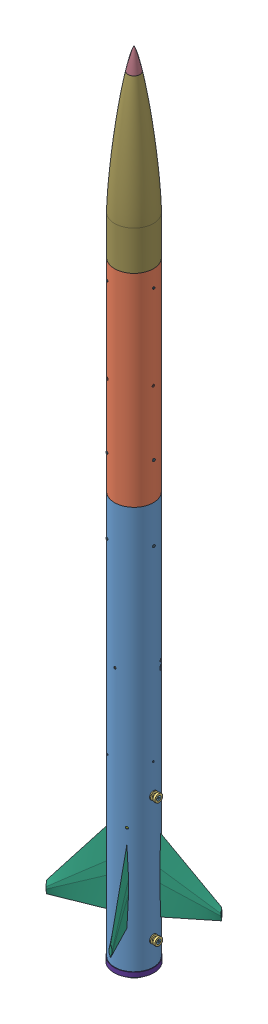
SolidWorks assembly Skipper_1B, configuration Default. Lengths in mm.
Overall size (229.44 1630.61 229.44).
187 component instances, 72 part files, 15 mates.
Components (placement in the parent):
- S1B_Airframe-1: S1B_Airframe [Default] at origin size (229.44 1236.87 229.44)
  - S1B_Aft_Body_Tube-2: S1B_Aft_Body_Tube [Default] at origin size (79.25 822.53 79.25)
  - S1B_Forward_Body_Tube-1: S1B_Forward_Body_Tube [Default] at (0 822.5282 0) size (79.25 414.34 79.25)
  - S1B_Railguide-1: S1B_Railguide [Default] at (39.8526 50.8 0) size (19.05 19 19)
    - S1B_Railguide_Bolt-1: S1B_Railguide_Bolt [Default] at origin size (10.92 16 16)
    - S1B_Welded_Nut_Railguide-1: S1B_Welded_Nut_Railguide [Default] at (-2.6264 0 0) x (0 0 1) z (-1 0 0) size (19 19 11)
    - S1B_10-32_Flathead_RailguideScrew-2: S1B_10-32_Flathead_RailguideScrew [91099A365] at (1.397 0 0) x (-1 0 0) z (0 0 -1) size (19.05 8.95 8.95)
  - S1B_Railguide-2: S1B_Railguide [Default] at (39.8526 304.8 0) size (19.05 19 19)
    - S1B_Railguide_Bolt-1: S1B_Railguide_Bolt [Default] at origin size (10.92 16 16)
    - S1B_Welded_Nut_Railguide-1: S1B_Welded_Nut_Railguide [Default] at (-2.6264 0 0) x (0 0 1) z (-1 0 0) size (19 19 11)
    - S1B_10-32_Flathead_RailguideScrew-2: S1B_10-32_Flathead_RailguideScrew [91099A365] at (1.397 0 0) x (-1 0 0) z (0 0 -1) size (19.05 8.95 8.95)
  - S1B_Fin_Representation_2-2: S1B_Fin_Representation_2 [Default] at (19.812 150.622 34.3154) x (0.5 0 0.866025) z (-0.866025 0 0.5) size (91.39 148.58 5.04)
  - S1B_Fin_Representation_2-3: S1B_Fin_Representation_2 [Default] at (-34.3154 150.622 19.812) x (-0.866025 0 0.5) z (-0.5 0 -0.866025) size (91.39 148.58 5.04)
  - S1B_Fin_Representation_2-4: S1B_Fin_Representation_2 [Default] at (-19.812 150.622 -34.3154) x (-0.5 0 -0.866025) z (0.866025 0 -0.5) size (91.39 148.58 5.04)
  - S1B_Fin_Representation_2-5: S1B_Fin_Representation_2 [Default] at (34.3154 150.622 -19.812) x (0.866025 0 -0.5) z (0.5 0 0.866025) size (91.39 148.58 5.04)
- S1B_Nose_Cone-1: S1B_Nose_Cone [Default] at (0 1169.2636 0) size (80.74 442.25 79.45)
  - S1B_Nose_Cone_Shoulder_Tube-1: S1B_Nose_Cone_Shoulder_Tube [Default] at origin size (76.28 147.82 76.28)
  - S1B_Nose_Cone_Bulkhead-1: S1B_Nose_Cone_Bulkhead [Default] at (0 141.4653 0) size (73.03 6.35 73.03)
  - S1B_Nose_Cone_Recovery_Eyebolt_3014T45_Steel Eyebolt with Shoulder - for Lifting-1: S1B_Nose_Cone_Recovery_Eyebolt_3014T45_Steel Eyebolt with Shoulder - for Lifting [3014T45] at (0 117.6528 0) x (-1 0 0) z (0 0 1) size (30.16 64.29 14.29)
  - S1B_Nose_Cone_Recovery_Nut_95462A029_Medium-Strength Steel Hex Nut-1: S1B_Nose_Cone_Recovery_Nut_95462A029_Medium-Strength Steel Hex Nut [95462A029] at (0 151.6856 0) x (1 0 0) z (0 1 0) size (11.11 12.83 5.56)
  - S1B_Nose_Cone_Recovery_Washer_90107A029_316 Stainless Steel Washer-1: S1B_Nose_Cone_Recovery_Washer_90107A029_316 Stainless Steel Washer [90107A029] at (0 147.8153 0) x (-1 0 0) z (0 0 -1) size (15.88 1.09 15.88)
  - S1B_Nose_Cone-1: S1B_Nose_Cone [Default] at (0 442.2522 0) x (0 -1 0) z (0 0 -1) size (330.2 79.45 79.45)
  - S1B_Nose_Cone_Tip-1: S1B_Nose_Cone_Tip [Default] at (0 442.2521 0) x (0 -1 0) z (0 0 1) size (44.45 24.48 24.48)
  - S1B_Shear_Pin-1: S1B_Shear_Pin [Default] at (39.7256 33.8074 0) x (0 -1 0) z (-1 0 0) size (3.81 3.83 10.38)
  - S1B_Shear_Pin-2: S1B_Shear_Pin [Default] at (-19.8628 33.8074 -34.4034) x (0 -1 0) z (0.5 0 0.866025) size (3.81 3.83 10.38)
  - S1B_Shear_Pin-3: S1B_Shear_Pin [Default] at (-19.8628 33.8074 34.4034) x (0 -1 0) z (0.5 0 -0.866025) size (3.81 3.83 10.38)
- S1B_Electronics_Bay-1: S1B_Electronics_Bay [Default] at (0 387.6803 0) size (104.18 564.06 103.27)
  - S1B_Electronics_Bay_Aft_Bulkhead-1: S1B_Electronics_Bay_Aft_Bulkhead [Default] at origin size (76.45 6.35 76.45)
  - S1B_Electronics_Bay_Spacer_Aft_Bulkhead-1: S1B_Electronics_Bay_Spacer_Aft_Bulkhead [Default] at (0 353.8981 0) size (76.71 9.53 76.71)
  - S1B_Electronics_Bay_Spacer_Forward_Bulkhead-1: S1B_Electronics_Bay_Spacer_Forward_Bulkhead [Default] at (0 506.2727 0) size (76.71 9.53 76.71)
  - S1B_Fat_Bulkhead_Coupler-2: S1B_Fat_Bulkhead_Coupler [Default] at (0 363.4231 0) size (76.45 142.85 76.45)
  - S1B_Electronics_Bay_3014T45_Steel Eyebolt with Shoulder - for Lifting-1: S1B_Electronics_Bay_3014T45_Steel Eyebolt with Shoulder - for Lifting [3014T45] at (0 539.6102 18.415) size (30.16 64.29 14.29)
  - S1B_Electronics_Bay_90107A029_316 Stainless Steel Washer-1: S1B_Electronics_Bay_90107A029_316 Stainless Steel Washer [90107A029] at (0 505.1805 18.415) x (-1 0 0) z (0 0 -1) size (15.88 1.09 15.88)
  - S1B_Electronics_Bay_95462A029_Medium-Strength Steel Hex Nut-1: S1B_Electronics_Bay_95462A029_Medium-Strength Steel Hex Nut [95462A029] at (0 502.4024 18.415) x (1 0 0) z (0 1 0) size (11.11 12.83 5.56)
  - S1B_Electronics_Bay_98804A006_18-8 Stainless Steel Threaded Rod-1: S1B_Electronics_Bay_98804A006_18-8 Stainless Steel Threaded Rod [98804A006] at (0 257.975 -29.464) x (1 0 0) z (0 -1 0) size (3.17 3.17 534.7)
  - S1B_Electronics_Bay_91841A006_18-8 Stainless Steel Hex Nut-1: S1B_Electronics_Bay_91841A006_18-8 Stainless Steel Hex Nut [91841A006] at (0 517.8218 -29.464) x (-1 0 0) z (0 0 -1) size (7.94 2.78 9.17)
  - S1B_Electronics_Bay_90107A006_316 Stainless Steel Washer-1: S1B_Electronics_Bay_90107A006_316 Stainless Steel Washer [90107A006] at (0 515.7977 -29.464) size (7.14 0.64 7.14)
  - S1B_Electronics_Bay_90107A006_316 Stainless Steel Washer-4: S1B_Electronics_Bay_90107A006_316 Stainless Steel Washer [90107A006] at (25.5166 515.7977 14.732) x (-0.5 0 0.866025) z (-0.866025 0 -0.5) size (7.14 0.64 7.14)
  - S1B_Electronics_Bay_90107A006_316 Stainless Steel Washer-5: S1B_Electronics_Bay_90107A006_316 Stainless Steel Washer [90107A006] at (-25.5166 515.7977 14.732) x (-0.5 0 -0.866025) z (0.866025 0 -0.5) size (7.14 0.64 7.14)
  - S1B_Electronics_Bay_91841A006_18-8 Stainless Steel Hex Nut-2: S1B_Electronics_Bay_91841A006_18-8 Stainless Steel Hex Nut [91841A006] at (25.5166 517.8218 14.732) x (0.5 0 -0.866025) z (0.866025 0 0.5) size (7.94 2.78 9.17)
  - S1B_Electronics_Bay_91841A006_18-8 Stainless Steel Hex Nut-3: S1B_Electronics_Bay_91841A006_18-8 Stainless Steel Hex Nut [91841A006] at (-25.5166 517.8218 14.732) x (0.5 0 0.866025) z (-0.866025 0 0.5) size (7.94 2.78 9.17)
  - S1B_Electronics_Bay_98804A006_18-8 Stainless Steel Threaded Rod-4: S1B_Electronics_Bay_98804A006_18-8 Stainless Steel Threaded Rod [98804A006] at (25.5166 257.975 14.732) x (-0.5 0 0.866025) z (0 -1 0) size (3.17 3.17 534.7)
  - S1B_Electronics_Bay_98804A006_18-8 Stainless Steel Threaded Rod-5: S1B_Electronics_Bay_98804A006_18-8 Stainless Steel Threaded Rod [98804A006] at (-25.5166 257.975 14.732) x (-0.5 0 -0.866025) z (0 -1 0) size (3.17 3.17 534.7)
  - S1B_Electronics_Bay_90107A006_316 Stainless Steel Washer-12: S1B_Electronics_Bay_90107A006_316 Stainless Steel Washer [90107A006] at (0 0 -29.464) x (1 0 0) z (0 0 -1) size (7.14 0.64 7.14)
  - S1B_Electronics_Bay_91841A006_18-8 Stainless Steel Hex Nut-14: S1B_Electronics_Bay_91841A006_18-8 Stainless Steel Hex Nut [91841A006] at (0 -2.0241 -29.464) x (-1 0 0) z (0 0 1) size (7.94 2.78 9.17)
  - S1B_Electronics_Bay_90107A006_316 Stainless Steel Washer-13: S1B_Electronics_Bay_90107A006_316 Stainless Steel Washer [90107A006] at (25.5166 0 14.732) x (-0.5 0 0.866025) z (0.866025 0 0.5) size (7.14 0.64 7.14)
  - S1B_Electronics_Bay_90107A006_316 Stainless Steel Washer-14: S1B_Electronics_Bay_90107A006_316 Stainless Steel Washer [90107A006] at (-25.5166 0 14.732) x (-0.5 0 -0.866025) z (-0.866025 0 0.5) size (7.14 0.64 7.14)
  - S1B_Electronics_Bay_91841A006_18-8 Stainless Steel Hex Nut-15: S1B_Electronics_Bay_91841A006_18-8 Stainless Steel Hex Nut [91841A006] at (25.5166 -2.0241 14.732) x (0.5 0 -0.866025) z (-0.866025 0 -0.5) size (7.94 2.78 9.17)
  - S1B_Electronics_Bay_91841A006_18-8 Stainless Steel Hex Nut-16: S1B_Electronics_Bay_91841A006_18-8 Stainless Steel Hex Nut [91841A006] at (-25.5166 -2.0241 14.732) x (0.5 0 0.866025) z (0.866025 0 -0.5) size (7.94 2.78 9.17)
  - S1B_Electronics_Bay_Avionics_Stack-1: S1B_Electronics_Bay_Avionics_Stack [Default] at (8.2928 -12.2914 -69.8691) size (104.18 344.14 103.27)
    - S1B_Flight_Power_Stack_Assy-1: S1B_Flight_Power_Stack_Assy [Default] at (-4.2933 16.5157 -11.6983) size (58.99 80 57.67)
      - S1B_Power_Stack-1: S1B_Power_Stack [Default] at (-4.1095 89.1616 81.6309) size (58.99 80 52.18)
      - S1B_9V Battery-1: S1B_9V Battery [Default] at (-5.5953 51.787 105.8736) x (0 0 -1) z (0 -1 0) size (47.57 16.87 26.11)
      - S1B_LiPo_A1-1: S1B_LiPo_A1 [Default] at (-22.7297 11.3191 64.2994) x (0 1 0) z (0 0 -1) size (72.97 12.27 33.73)
      - S1B_9V Battery-2: S1B_9V Battery [Default] at (-5.5953 23.6758 105.8736) x (0 0 -1) z (0 -1 0) size (47.57 16.87 26.11)
    - S1B_Fight_Computer_Stack_Assy-1: S1B_Fight_Computer_Stack_Assy [Default] at (37.1119 269.2904 8.8488) x (0.5 0 0.866025) z (0 -1 0) size (74.68 77.18 120)
      - S1B_6.86mm_Nut_3mm_Hole-7: S1B_6.86mm_Nut_3mm_Hole [Default] at (49.4605 62.5264 50.3494) x (0.433013 -0.75 0.5) z (-0.25 0.433013 0.866025) size (7.92 1.91 6.86)
      - S1B_6.86mm_Nut_3mm_Hole-10: S1B_6.86mm_Nut_3mm_Hole [Default] at (38.5881 85.168 145.066) x (-0.433013 0.75 -0.5) z (-0.25 0.433013 0.866025) size (7.92 1.91 6.86)
      - S1B_6.86mm_Nut_3mm_Hole-11: S1B_6.86mm_Nut_3mm_Hole [Default] at (36.9383 84.2155 50.3494) x (0.433013 -0.75 -0.5) z (0.25 -0.433013 0.866025) size (7.92 1.91 6.86)
      - S1B_6.86mm_Nut_3mm_Hole-12: S1B_6.86mm_Nut_3mm_Hole [Default] at (49.4605 62.5264 145.066) x (0.433013 -0.75 -0.5) z (0.25 -0.433013 0.866025) size (7.92 1.91 6.86)
      - S1B_Ruber_Washer_3mm-5: S1B_Ruber_Washer_3mm [Default] at (53.7083 64.9789 145.066) x (-0.5 0.866025 0) z (0 0 1) size (6 1.25 6)
      - S1B_Ruber_Washer_3mm-6: S1B_Ruber_Washer_3mm [Default] at (41.1861 86.668 145.066) x (-0.5 0.866025 0) z (0 0 1) size (6 1.25 6)
      - S1B_Ruber_Washer_3mm-7: S1B_Ruber_Washer_3mm [Default] at (53.7083 64.9789 50.3494) x (-0.5 0.866025 0) z (0 0 1) size (6 1.25 6)
      - S1B_Ruber_Washer_3mm-8: S1B_Ruber_Washer_3mm [Default] at (41.1861 86.668 50.3494) x (-0.5 0.866025 0) z (0 0 1) size (6 1.25 6)
      - S1B_Avionics_Stack - AIM-1: S1B_Avionics_Stack - AIM [Default] at (55.5493 84.6273 26.5774) x (-0.5 -0.866025 0) z (0 0 1) size (33.58 52.18 120)
      - S1B_AimXtra-1: S1B_AimXtra [Default] at (39.9161 88.8677 47.8094) x (0 0 1) z (-0.5 0.866025 0) size (102.34 16.13 30.12)
      - S1B_6.86mm_Nut_3mm_Hole-13: S1B_6.86mm_Nut_3mm_Hole [Default] at (13.2223 66.1787 125.5587) x (0.433013 0.75 -0.5) z (0.25 0.433013 0.866025) size (7.92 1.91 6.86)
      - S1B_6.86mm_Nut_3mm_Hole-14: S1B_6.86mm_Nut_3mm_Hole [Default] at (24.7223 86.0973 125.5587) x (0.433013 0.75 -0.5) z (0.25 0.433013 0.866025) size (7.92 1.91 6.86)
      - S1B_6.86mm_Nut_3mm_Hole-15: S1B_6.86mm_Nut_3mm_Hole [Default] at (13.2223 66.1787 69.0624) x (0.433013 0.75 0.5) z (-0.25 -0.433013 0.866025) size (7.92 1.91 6.86)
      - S1B_6.86mm_Nut_3mm_Hole-16: S1B_6.86mm_Nut_3mm_Hole [Default] at (24.7223 86.0973 67.5587) x (0.433013 0.75 -0.5) z (0.25 0.433013 0.866025) size (7.92 1.91 6.86)
      - S1B_Ruber_Washer_3mm-9: S1B_Ruber_Washer_3mm [Default] at (21.3404 88.0498 67.5587) x (0.5 0.866025 0) z (0 0 1) size (6 1.25 6)
      - S1B_Ruber_Washer_3mm-10: S1B_Ruber_Washer_3mm [Default] at (9.8404 68.1312 69.0624) x (0.5 0.866025 0) z (0 0 1) size (6 1.25 6)
      - S1B_Ruber_Washer_3mm-11: S1B_Ruber_Washer_3mm [Default] at (21.3404 88.0498 125.5587) x (0.5 0.866025 0) z (0 0 1) size (6 1.25 6)
      - S1B_Ruber_Washer_3mm-12: S1B_Ruber_Washer_3mm [Default] at (9.8404 68.1312 125.5587) x (0.5 0.866025 0) z (0 0 1) size (6 1.25 6)
      - S1B_Avionics_Stack-1: S1B_Avionics_Stack [Default] at (4.7361 84.6273 26.5774) size (33.58 52.18 120)
      - S1B_RBP2W-1: S1B_RBP2W [Default] at (13.9471 81.3442 101.7819) x (0 0 -1) z (0.5 0.866025 0) size (65 5.1 31.05)
      - S1B_6.86mm_Nut_3mm_Hole-17: S1B_6.86mm_Nut_3mm_Hole [Default] at (44.7248 57.1953 44.9616) x (-0.868623 0 -0.495473) z (-0.495473 0 0.868623) size (7.92 1.91 6.86)
      - S1B_6.86mm_Nut_3mm_Hole-18: S1B_6.86mm_Nut_3mm_Hole [Default] at (44.7248 57.1953 59.1316) x (-0.868623 0 -0.495473) z (-0.495473 0 0.868623) size (7.92 1.91 6.86)
      - S1B_6.86mm_Nut_3mm_Hole-19: S1B_6.86mm_Nut_3mm_Hole [Default] at (12.4948 57.1953 59.1316) x (-0.868623 0 -0.495473) z (-0.495473 0 0.868623) size (7.92 1.91 6.86)
      - S1B_6.86mm_Nut_3mm_Hole-20: S1B_6.86mm_Nut_3mm_Hole [Default] at (12.4948 57.1953 44.9616) x (-0.855922 0 -0.517105) z (-0.517105 0 0.855922) size (7.92 1.91 6.86)
      - S1B_Ruber_Washer_3mm-13: S1B_Ruber_Washer_3mm [Default] at (12.4948 52.0403 44.9616) size (6 1.25 6)
      - S1B_Ruber_Washer_3mm-14: S1B_Ruber_Washer_3mm [Default] at (44.7248 52.0403 44.9616) size (6 1.25 6)
      - S1B_Ruber_Washer_3mm-15: S1B_Ruber_Washer_3mm [Default] at (44.7248 52.0403 59.1316) size (6 1.25 6)
      - S1B_Ruber_Washer_3mm-16: S1B_Ruber_Washer_3mm [Default] at (12.4948 52.0403 59.1316) size (6 1.25 6)
      - S1B_Avionics_Stack - EasyMini-1: S1B_Avionics_Stack - EasyMini [Default] at (30.1427 40.6218 26.5774) x (-0.5 0.866025 0) z (0 0 1) size (33.58 52.18 120)
      - S1B_EZMINI-1: S1B_EZMINI [Default] at (28.7345 50.2403 46.2994) x (1 0 0) z (0 0 -1) size (38.23 12.5 21.18)
    - S1B_Sensor_Power_Stack_Assy-1: S1B_Sensor_Power_Stack_Assy [Default] at (-32.7742 223.4603 27.9192) size (57.8 36.27 57.54)
      - S1B_Sensor_Power_Stack-1: S1B_Sensor_Power_Stack [Default] at (24.3714 13.7485 42.0133) size (57.8 28.96 55.69)
      - S1B_9V Battery-1: S1B_9V Battery [Default] at (37.7064 32.0365 66.7275) x (0 0 -1) z (1 0 0) size (47.57 16.87 26.11)
      - S1B_9V Battery-2: S1B_9V Battery [Default] at (37.7064 12.6309 66.7275) x (0 0 -1) z (1 0 0) size (47.57 16.87 26.11)
    - S1B_Sensor_Stack_Assy-1: S1B_Sensor_Stack_Assy [Default] at (-68.238 266.8297 115.4931) x (-0.5 0 -0.866025) z (0.866025 0 -0.5) size (58.99 80 52.18)
      - S1B_Sensor_Stack_T_Mount_A2-1: S1B_Sensor_Stack_T_Mount_A2 [Default] at (9.5389 -1.0891 74.5991) size (58.99 80 52.18)
      - S1B_6.86mm_Nut_3mm_Hole-1: S1B_6.86mm_Nut_3mm_Hole [Default] at (6.8862 79.7859 74.7996) x (0.75 0.5 0.433013) z (0.433013 -0.866025 0.25) size (7.92 1.91 6.86)
      - S1B_Ruber_Washer_3mm-1: S1B_Ruber_Washer_3mm [Default] at (28.3048 79.7859 83.7015) x (0.75 -0.5 0.433013) z (0.433013 0.866025 0.25) size (6 1.25 6)
      - S1B_Ruber_Washer_3mm-2: S1B_Ruber_Washer_3mm [Default] at (8.3862 79.7859 72.2015) x (0.75 -0.5 0.433013) z (0.433013 0.866025 0.25) size (6 1.25 6)
      - S1B_Ruber_Washer_3mm-3: S1B_Ruber_Washer_3mm [Default] at (28.3048 18.0359 83.7015) x (0.75 -0.5 0.433013) z (0.433013 0.866025 0.25) size (6 1.25 6)
      - S1B_Ruber_Washer_3mm-4: S1B_Ruber_Washer_3mm [Default] at (8.3862 18.0359 72.2015) x (0.75 -0.5 0.433013) z (0.433013 0.866025 0.25) size (6 1.25 6)
      - S1B_6.86mm_Nut_3mm_Hole-3: S1B_6.86mm_Nut_3mm_Hole [Default] at (26.8048 18.0359 86.2996) x (0.75 0.5 0.433013) z (0.433013 -0.866025 0.25) size (7.92 1.91 6.86)
      - S1B_6.86mm_Nut_3mm_Hole-4: S1B_6.86mm_Nut_3mm_Hole [Default] at (6.8862 18.0359 74.7996) x (0.75 0.5 0.433013) z (0.433013 -0.866025 0.25) size (7.92 1.91 6.86)
      - S1B_6.86mm_Nut_3mm_Hole-2: S1B_6.86mm_Nut_3mm_Hole [Default] at (26.8048 79.7859 86.2996) x (0.75 0.5 0.433013) z (0.433013 -0.866025 0.25) size (7.92 1.91 6.86)
      - S1B_Sensor_PCB-1: S1B_Sensor_PCB [Default] at (32.9609 14.7859 82.637) x (0 1 0) z (0.866025 0 0.5) size (68.25 2 30)
    - S1B_Blue_Damper-1: S1B_Blue_Damper [Default] at (-33.8094 18.6414 84.6011) x (0 0 -1) z (1 0 0) size (9.3 7.04 9.3)
    - S1B_Blue_Damper-19: S1B_Blue_Damper [Default] at (-33.8094 105.6772 84.6011) size (9.3 7.04 9.3)
    - S1B_Blue_Damper-22: S1B_Blue_Damper [Default] at (-33.8094 232.713 84.6011) size (9.3 7.04 9.3)
    - S1B_Blue_Damper-25: S1B_Blue_Damper [Default] at (-33.8094 268.7048 84.6011) x (-1 0 0) z (0 0 -1) size (9.3 7.04 9.3)
    - S1B_Blue_Damper-28: S1B_Blue_Damper [Default] at (-33.8094 355.7406 84.6011) size (9.3 7.04 9.3)
    - S1B_Blue_Damper-29: S1B_Blue_Damper [Default] at (17.1065 355.7406 84.4952) x (-0.5 0 -0.866025) z (0.866025 0 -0.5) size (9.3 7.04 9.3)
    - S1B_Blue_Damper-30: S1B_Blue_Damper [Default] at (-8.4431 355.7406 40.4537) x (-0.5 0 0.866025) z (-0.866025 0 -0.5) size (9.3 7.04 9.3)
    - S1B_Blue_Damper-26: S1B_Blue_Damper [Default] at (17.1065 268.7048 84.4952) x (0.5 0 0.866025) z (-0.866025 0 0.5) size (9.3 7.04 9.3)
    - S1B_Blue_Damper-27: S1B_Blue_Damper [Default] at (-8.4431 268.7048 40.4537) x (0.5 0 -0.866025) z (0.866025 0 0.5) size (9.3 7.04 9.3)
    - S1B_Blue_Damper-23: S1B_Blue_Damper [Default] at (17.1065 232.713 84.4952) x (-0.5 0 -0.866025) z (0.866025 0 -0.5) size (9.3 7.04 9.3)
    - S1B_Blue_Damper-24: S1B_Blue_Damper [Default] at (-8.4431 232.713 40.4537) x (-0.5 0 0.866025) z (-0.866025 0 -0.5) size (9.3 7.04 9.3)
    - S1B_Blue_Damper-20: S1B_Blue_Damper [Default] at (17.1065 105.6772 84.4952) x (-0.5 0 -0.866025) z (0.866025 0 -0.5) size (9.3 7.04 9.3)
    - S1B_Blue_Damper-21: S1B_Blue_Damper [Default] at (-8.4431 105.6772 40.4537) x (-0.5 0 0.866025) z (-0.866025 0 -0.5) size (9.3 7.04 9.3)
    - S1B_Blue_Damper-17: S1B_Blue_Damper [Default] at (17.1065 18.6414 84.4952) x (-0.866025 0 0.5) z (-0.5 0 -0.866025) size (9.3 7.04 9.3)
    - S1B_Blue_Damper-18: S1B_Blue_Damper [Default] at (-8.4431 18.6414 40.4537) x (0.866025 0 0.5) z (-0.5 0 0.866025) size (9.3 7.04 9.3)
  - S1B_Airframe_Threaded_Inserts_92394A113_18-8 Stainless Steel Screw-to-Expand Insert for Plastic-1: S1B_Airframe_Threaded_Inserts_92394A113_18-8 Stainless Steel Screw-to-Expand Insert for Plastic [92394A113] at (-17.5895 358.6606 -30.4659) x (0 -1 0) z (0.866025 0 -0.5) size (5.05 6.35 5.05)
  - S1B_Airframe_Bolts_90357A120_Ultra-Low-Profile Socket Head Screw-1: S1B_Airframe_Bolts_90357A120_Ultra-Low-Profile Socket Head Screw [90357A120] at (-18.3483 358.6606 -31.7802) x (0.866025 0 -0.5) z (0.5 0 0.866025) size (5.08 5.08 9.2)
  - S1B_Airframe_Threaded_Inserts_92394A113_18-8 Stainless Steel Screw-to-Expand Insert for Plastic-2: S1B_Airframe_Threaded_Inserts_92394A113_18-8 Stainless Steel Screw-to-Expand Insert for Plastic [92394A113] at (35.179 358.6606 0) x (0 -1 0) z (0 0 1) size (5.05 6.35 5.05)
  - S1B_Airframe_Threaded_Inserts_92394A113_18-8 Stainless Steel Screw-to-Expand Insert for Plastic-6: S1B_Airframe_Threaded_Inserts_92394A113_18-8 Stainless Steel Screw-to-Expand Insert for Plastic [92394A113] at (-17.5895 358.6606 30.4659) x (0 -1 0) z (-0.866025 0 -0.5) size (5.05 6.35 5.05)
  - S1B_Airframe_Bolts_90357A120_Ultra-Low-Profile Socket Head Screw-2: S1B_Airframe_Bolts_90357A120_Ultra-Low-Profile Socket Head Screw [90357A120] at (36.6966 358.6606 0) x (0 0 1) z (-1 0 0) size (5.08 5.08 9.2)
  - S1B_Airframe_Bolts_90357A120_Ultra-Low-Profile Socket Head Screw-6: S1B_Airframe_Bolts_90357A120_Ultra-Low-Profile Socket Head Screw [90357A120] at (-18.3483 358.6606 31.7802) x (-0.866025 0 -0.5) z (0.5 0 -0.866025) size (5.08 5.08 9.2)
  - S1B_Airframe_Bolts_90357A120_Ultra-Low-Profile Socket Head Screw-8: S1B_Airframe_Bolts_90357A120_Ultra-Low-Profile Socket Head Screw [90357A120] at (-18.3483 511.0606 -31.7802) x (0.866025 0 -0.5) z (0.5 0 0.866025) size (5.08 5.08 9.2)
  - S1B_Airframe_Threaded_Inserts_92394A113_18-8 Stainless Steel Screw-to-Expand Insert for Plastic-8: S1B_Airframe_Threaded_Inserts_92394A113_18-8 Stainless Steel Screw-to-Expand Insert for Plastic [92394A113] at (-17.5895 511.0606 -30.4659) x (0 -1 0) z (0.866025 0 -0.5) size (5.05 6.35 5.05)
  - S1B_Airframe_Threaded_Inserts_92394A113_18-8 Stainless Steel Screw-to-Expand Insert for Plastic-5: S1B_Airframe_Threaded_Inserts_92394A113_18-8 Stainless Steel Screw-to-Expand Insert for Plastic [92394A113] at (35.179 511.0606 0) x (0 -1 0) z (0 0 1) size (5.05 6.35 5.05)
  - S1B_Airframe_Threaded_Inserts_92394A113_18-8 Stainless Steel Screw-to-Expand Insert for Plastic-7: S1B_Airframe_Threaded_Inserts_92394A113_18-8 Stainless Steel Screw-to-Expand Insert for Plastic [92394A113] at (-17.5895 511.0606 30.4659) x (0 -1 0) z (-0.866025 0 -0.5) size (5.05 6.35 5.05)
  - S1B_Airframe_Bolts_90357A120_Ultra-Low-Profile Socket Head Screw-5: S1B_Airframe_Bolts_90357A120_Ultra-Low-Profile Socket Head Screw [90357A120] at (36.6966 511.0606 0) x (0 0 1) z (-1 0 0) size (5.08 5.08 9.2)
  - S1B_Airframe_Bolts_90357A120_Ultra-Low-Profile Socket Head Screw-7: S1B_Airframe_Bolts_90357A120_Ultra-Low-Profile Socket Head Screw [90357A120] at (-18.3483 511.0606 31.7802) x (-0.866025 0 -0.5) z (0.5 0 -0.866025) size (5.08 5.08 9.2)
  - S1B_Peregrine_DualPeregrine_Threaded_Inserts_92394A101_18-8 Stainless Steel Screw-to-Expand Insert for Plastic-1: S1B_Peregrine_DualPeregrine_Threaded_Inserts_92394A101_18-8 Stainless Steel Screw-to-Expand Insert for Plastic [92394A101] at (0 511.0352 0) x (-1 0 0) z (0 0 -1) size (6.65 9.53 6.65)
  - S1B_Peregrine_DualPeregrine_Threaded_Inserts_92394A101_18-8 Stainless Steel Screw-to-Expand Insert for Plastic-2: S1B_Peregrine_DualPeregrine_Threaded_Inserts_92394A101_18-8 Stainless Steel Screw-to-Expand Insert for Plastic [92394A101] at (0 511.0352 -20.32) x (-1 0 0) z (0 0 -1) size (6.65 9.53 6.65)
  - S1B_O_Ring_Seal_with_Captured_Nuts-1: S1B_O_Ring_Seal_with_Captured_Nuts [Default] at (0 515.7977 0) size (76.2 14.25 76.2)
  - S1B_Electronics_Bay_90107A006_316 Stainless Steel Washer-9: S1B_Electronics_Bay_90107A006_316 Stainless Steel Washer [90107A006] at (0 353.2631 -29.464) size (7.14 0.64 7.14)
  - S1B_Electronics_Bay_91841A006_18-8 Stainless Steel Hex Nut-10: S1B_Electronics_Bay_91841A006_18-8 Stainless Steel Hex Nut [91841A006] at (0 351.8741 -29.464) x (-1 0 0) z (0 0 -1) size (7.94 2.78 9.17)
  - S1B_Electronics_Bay_91841A006_18-8 Stainless Steel Hex Nut-12: S1B_Electronics_Bay_91841A006_18-8 Stainless Steel Hex Nut [91841A006] at (25.5166 351.8741 14.732) x (0.5 0 -0.866025) z (0.866025 0 0.5) size (7.94 2.78 9.17)
  - S1B_Electronics_Bay_91841A006_18-8 Stainless Steel Hex Nut-13: S1B_Electronics_Bay_91841A006_18-8 Stainless Steel Hex Nut [91841A006] at (-25.5166 351.8741 14.732) x (0.5 0 0.866025) z (-0.866025 0 0.5) size (7.94 2.78 9.17)
  - S1B_Electronics_Bay_90107A006_316 Stainless Steel Washer-10: S1B_Electronics_Bay_90107A006_316 Stainless Steel Washer [90107A006] at (25.5166 353.2631 14.732) x (-0.5 0 0.866025) z (-0.866025 0 -0.5) size (7.14 0.64 7.14)
  - S1B_Electronics_Bay_90107A006_316 Stainless Steel Washer-11: S1B_Electronics_Bay_90107A006_316 Stainless Steel Washer [90107A006] at (-25.5166 353.2631 14.732) x (-0.5 0 -0.866025) z (0.866025 0 -0.5) size (7.14 0.64 7.14)
  - S1B_9452K159_Oil-Resistant Buna-N O-Ring-1: S1B_9452K159_Oil-Resistant Buna-N O-Ring [Default] at (0 520.4967 0) size (76.2 3.81 76.2)
  - S1B_Electronics_Bay_91841A006_18-8 Stainless Steel Hex Nut-17: S1B_Electronics_Bay_91841A006_18-8 Stainless Steel Hex Nut [91841A006] at (0 -4.8022 -29.464) x (0 0 -1) z (-1 0 0) size (7.94 2.78 9.17)
  - S1B_Electronics_Bay_91841A006_18-8 Stainless Steel Hex Nut-18: S1B_Electronics_Bay_91841A006_18-8 Stainless Steel Hex Nut [91841A006] at (25.5166 -4.8022 14.732) x (0.866025 0 0.5) z (0.5 0 -0.866025) size (7.94 2.78 9.17)
  - S1B_Electronics_Bay_91841A006_18-8 Stainless Steel Hex Nut-19: S1B_Electronics_Bay_91841A006_18-8 Stainless Steel Hex Nut [91841A006] at (-25.5166 -4.8022 14.732) x (-0.866025 0 0.5) z (0.5 0 0.866025) size (7.94 2.78 9.17)
  - S1B_Peregrine_Assembly-1: S1B_Peregrine_Assembly [Default] at (-12.7 515.7977 -10.16) size (53.34 129.45 29.79)
    - S1B_Peregrine_DualPeregrine_CO2_System_Cap-1: S1B_Peregrine_DualPeregrine_CO2_System_Cap [Default] at origin size (53.34 16.87 27.94)
    - S1B_Peregrine_CO2_System_Tube-1: S1B_Peregrine_CO2_System_Tube [Default] at origin size (23.62 104.52 23.62)
    - S1B_Peregrine_CO2_System_Tube-2: S1B_Peregrine_CO2_System_Tube [Default] at (25.4 0 0) size (23.62 104.52 23.62)
    - S1B_Peregrine_Capsule-2: S1B_Peregrine_Capsule [Default] at (25.4 -87.884 0) size (18.64 82.88 18.64)
    - S1B_Peregrine_Capsule-3: S1B_Peregrine_Capsule [Default] at (0 -87.884 0) size (18.64 82.88 18.64)
    - S1B_Peregrine_Charge_Cup-1: S1B_Peregrine_Charge_Cup [Default] at (25.4 -109.2708 0) size (18.85 16.36 18.85)
    - S1B_Peregrine_Charge_Cup-2: S1B_Peregrine_Charge_Cup [Default] at (0 -109.2708 0) size (18.85 16.36 18.85)
    - S1B_Peregrine_Lift_Piston-1: S1B_Peregrine_Lift_Piston [Default] at (25.4 -92.9132 0) size (20.08 9.25 20.08)
    - S1B_Peregrine_Lift_Piston-2: S1B_Peregrine_Lift_Piston [Default] at (0 -92.9132 0) size (20.08 9.25 20.08)
    - S1B_Peregrine_Alignment_Collar-1: S1B_Peregrine_Alignment_Collar [Default] at (25.4 -8.89 0) x (-1 0 0) z (0 0 1) size (18.8 9.7 18.8)
    - S1B_Peregrine_Alignment_Collar-2: S1B_Peregrine_Alignment_Collar [Default] at (0 -8.89 0) x (-1 0 0) z (0 0 1) size (18.8 9.7 18.8)
    - S1B_Peregrine_Spring-1: S1B_Peregrine_Spring [Default] at (25.4 -8.89 0) size (18.69 11.43 17.78)
    - S1B_Peregrine_Spring-2: S1B_Peregrine_Spring [Default] at (0 -8.89 0) size (18.69 11.43 17.78)
    - S1B_Peregrine_DualPeregrine_Mounting_Bolt_91772A247_Passivated 18-8 Stainless Steel Pan Head Phillips Screw-1: S1B_Peregrine_DualPeregrine_Mounting_Bolt_91772A247_Passivated 18-8 Stainless Steel Pan Head Phillips Screw [91772A247] at (12.7 -8.5344 -10.16) x (-1 0 0) z (0 1 0) size (9.47 9.47 28.89)
    - S1B_Peregrine_DualPeregrine_Mounting_Bolt_91772A247_Passivated 18-8 Stainless Steel Pan Head Phillips Screw-2: S1B_Peregrine_DualPeregrine_Mounting_Bolt_91772A247_Passivated 18-8 Stainless Steel Pan Head Phillips Screw [91772A247] at (12.7 -8.5344 10.16) x (1 0 0) z (0 1 0) size (9.47 9.47 28.89)
- S1B_Propulsion-1: S1B_Propulsion [Default] x (0 0 1) z (0 1 0) size (81.28 81.28 396.92)
  - S1B_Thrust_Block-1: S1B_Thrust_Block [Default] at (0 0 -9.525) x (1 0 0) z (0 1 0) size (81.28 9.53 81.28)
  - S1B_Motor_Casing_Centering_Ring-1: S1B_Motor_Casing_Centering_Ring [Default] at (0 0 209.55) x (0 1 0) z (-1 0 0) size (76.71 6.35 76.71)
  - S1B_Motor_Casing_Centering_Ring-2: S1B_Motor_Casing_Centering_Ring [Default] at (0 0 101.6) x (0 1 0) z (-1 0 0) size (76.71 6.35 76.71)
  - S1B_Propulsion_Forward_Bulkhead-1: S1B_Propulsion_Forward_Bulkhead [Default] at (0 0 355.6) x (1 0 0) z (0 -1 0) size (76.71 9.53 76.71)
  - S1B_Propulsion_Threaded_Rod_90322A682_High-Strength Steel Threaded Rod-1: S1B_Propulsion_Threaded_Rod_90322A682_High-Strength Steel Threaded Rod [90322A682] at (0 0 296.9006) x (0 -1 0) z (0 0 1) size (7.94 7.94 161.85)
  - S1B_Propulsion_Threaded_Rod_90107A030_316 Stainless Steel Washer-1: S1B_Propulsion_Threaded_Rod_90107A030_316 Stainless Steel Washer [90107A030] at (0 0 365.76) x (0 1 0) z (0 0 1) size (19.05 19.05 1.27)
  - S1B_Propulsion_Threaded_Rod_90107A030_316 Stainless Steel Washer-2: S1B_Propulsion_Threaded_Rod_90107A030_316 Stainless Steel Washer [90107A030] at (0 0 354.965) size (19.05 19.05 1.27)
  - S1B_Propulsion_Threaded_Rod_95505A602_Medium-Strength Steel Hex Nut-1: S1B_Propulsion_Threaded_Rod_95505A602_Medium-Strength Steel Hex Nut [95505A602] at (0 0 369.7684) size (12.7 14.66 6.75)
  - S1B_Propulsion_Threaded_Rod_95505A602_Medium-Strength Steel Hex Nut-2: S1B_Propulsion_Threaded_Rod_95505A602_Medium-Strength Steel Hex Nut [95505A602] at (0 0 350.9566) size (12.7 14.66 6.75)
  - S1B_Motor_and_Motor_Casing-1: S1B_Motor_and_Motor_Casing [Default] at (13.8939 243.3717 -65.3445) x (-1 0 0) z (0 -1 0) size (66.27 314.35 66.27)
    - S1B_Nozzle-1: S1B_Nozzle [Default] at (13.8939 -52.5907 243.3717) x (0.999876 0 -0.015724) z (-0.015724 0 -0.999876) size (50.55 26.47 50.55)
    - S1B_ForwardSealDisk-1: S1B_ForwardSealDisk [Default] at (13.8939 -253.0725 243.3717) x (0.999998 0 0.001834) z (-0.001834 0 0.999998) size (50.4 6.2 50.4)
    - S1B_S1AftClosure-1: S1B_S1AftClosure [Default] at (32.5939 -70.3251 243.3717) size (56.53 20.87 56.51)
    - S1B_CaseSpacer-1: S1B_CaseSpacer [Default] at (13.8939 -342.4625 243.3717) x (0.984366 0 0.176137) z (-0.176137 0 0.984366) size (50.35 83.14 50.35)
    - S1B_FloatingForwardClosure-1: S1B_FloatingForwardClosure [Default] at (13.8939 -253.0725 243.3717) x (0.109892 0 -0.993944) z (-0.993944 0 -0.109892) size (50 36.61 50)
    - S1B_Liner-1: S1B_Liner [Default] at (13.8939 -249.7325 243.3717) x (0.217736 0 0.976008) z (-0.976008 0 0.217736) size (50.7 177.66 50.7)
    - S1B_Grains CAD-1: S1B_Grains CAD [Default] at (13.8939 -246.8682 243.3717) x (0.314643 0 -0.94921) z (0.94921 0 0.314643) size (47 82.35 47)
    - S1B_Casing-2: S1B_Casing [Default] at (13.8939 -351.0945 243.3717) size (54 295.28 54)
    - S1B_Grains CAD-2: S1B_Grains CAD [Default] at (13.8939 -162.9237 243.3717) x (-0.810675 0 -0.585496) z (0.585496 0 -0.810675) size (47 82.35 47)
    - S1B_O-ringL-1: S1B_O-ringL [9452K62] at (13.8939 -67.7195 243.3717) x (0.157366 0 0.98754) z (0 1 0) size (51.1 51.1 3.53)
    - S1B_O-ringL-4: S1B_O-ringL [9452K62] at (13.8939 -254.5725 243.3717) x (0.948867 0 0.315675) z (0 1 0) size (51.1 51.1 3.53)
    - S1B_9452K118_Oil-Resistant Buna-N O-Ring (031)-1: S1B_9452K118_Oil-Resistant Buna-N O-Ring (031) [9452K118] at (13.8939 -248.3325 243.3717) x (0.860014 0 0.510271) z (0 1 0) size (47.73 47.73 1.78)
    - S1B_9452K118_Oil-Resistant Buna-N O-Ring (031)-2: S1B_9452K118_Oil-Resistant Buna-N O-Ring (031) [9452K118] at (13.8939 -79.7075 243.3717) x (-0.052255 0 0.998634) z (0 1 0) size (47.73 47.73 1.78)
    - S1B_9452K118_Oil-Resistant Buna-N O-Ring (031)-3: S1B_9452K118_Oil-Resistant Buna-N O-Ring (031) [9452K118] at (13.8939 -163.8682 243.3717) x (0.996802 0 0.079916) z (0 1 0) size (47.73 47.73 1.78)
    - S1B_S1AftClosure - Copy-1: S1B_S1AftClosure - Copy [Default] at (8.9907 -336.5889 261.4174) x (-0.262202 0 0.965013) z (0.965013 0 0.262202) size (54 20.81 54)
- S1B_Recovery_System_Representation-1: S1B_Recovery_System_Representation [Default] at (0 1055.878 0) size (76.2 203.2 76.2)
  - S1B_Main_Parachute_REPRESENTATION-1: S1B_Main_Parachute_REPRESENTATION [Default] at origin size (76.2 127 76.2)
  - S1B_Drogue_Parachute_REPRESENTATION-1: S1B_Drogue_Parachute_REPRESENTATION [Default] at (0 127 0) size (76.2 25.4 76.2)
  - S1B_Shock_Cord_and_Quick_Links_REPRESENTATION-1: S1B_Shock_Cord_and_Quick_Links_REPRESENTATION [Default] at (0 -50.8 0) size (50.8 101.6 50.8)
Mates (geometry in assembly coordinates):
- Coincident1: coincident anti-aligned: line of S1B_Airframe-1 through (110 0 55) axis (0 0 -1)
- Parallel1: parallel aligned: plane of S1B_Airframe-1 through (0 0 0) normal (0 0 1)
- Coincident2: coincident aligned: plane of S1B_Airframe-1 through (0 0 0) normal (0 1 0)
- Coincident3: coincident aligned: line of S1B_Nose_Cone-1 through (110 0 1114.2636) axis (0 0 1)
- Parallel2: parallel aligned: plane of S1B_Nose_Cone-1 through (0 1169.2636 0) normal (0 0 1)
- Coincident4: coincident anti-aligned: line of S1B_Electronics_Bay-1 through (6.985 0 426.1488) axis (0 0 -1)
- Parallel3: parallel aligned: plane of S1B_Electronics_Bay-1 through (0 387.6803 0) normal (0 0 1)
- Coincident5: coincident anti-aligned: plane of S1B_Airframe-1/S1B_Aft_Body_Tube-2 through (0 822.5282 0) normal (0 1 0); plane of S1A_Electronics_Bay-1/S1A_Fat_Bulkhead_Spacer-2 through (0 822.5282 0) normal (0 -1 0)
- Coincident7: coincident anti-aligned: line of S1B_Propulsion-1 through (396.0495 0 281.4193) axis (0 0 -1)
- Parallel4: parallel aligned: plane of S1B_Propulsion-1 through (0 0 0) normal (0 0 1)
- Coincident8: coincident anti-aligned: plane of S1B_Airframe-1/S1B_Forward_Body_Tube-1 through (0 1236.8657 0) normal (0 1 0); plane of S1B_Nose_Cone-1/S1B_Nose_Cone-1 through (0 1236.8657 0) normal (0 -1 0)
- Coincident9: coincident anti-aligned: plane of S1B_Airframe-1/S1B_Aft_Body_Tube-2 through (0 0 0) normal (0 -1 0); plane of S1A_Propulsion-1/S1A_Aft_Adaptor_Ring-1 through (0 0 26.924) normal (0 1 0)
- Coincident10: coincident anti-aligned: line of S1B_Recovery_System_Representation-1 through (110 0 1110.878) axis (0 0 -1)
- Parallel5: parallel aligned: plane of S1B_Recovery_System_Representation-1 through (0 1055.878 0) normal (0 0 1)
- Distance1: distance = 152.4 mm aligned: plane of S1B_Recovery_System_Representation-1 through (0 1055.878 0) normal (0 1 0); plane of S1B_Electronics_Bay-1/S1B_Electronics_Bay_Spacer_Forward_Bulkhead-1 through (0 903.478 0) normal (0 1 0)
